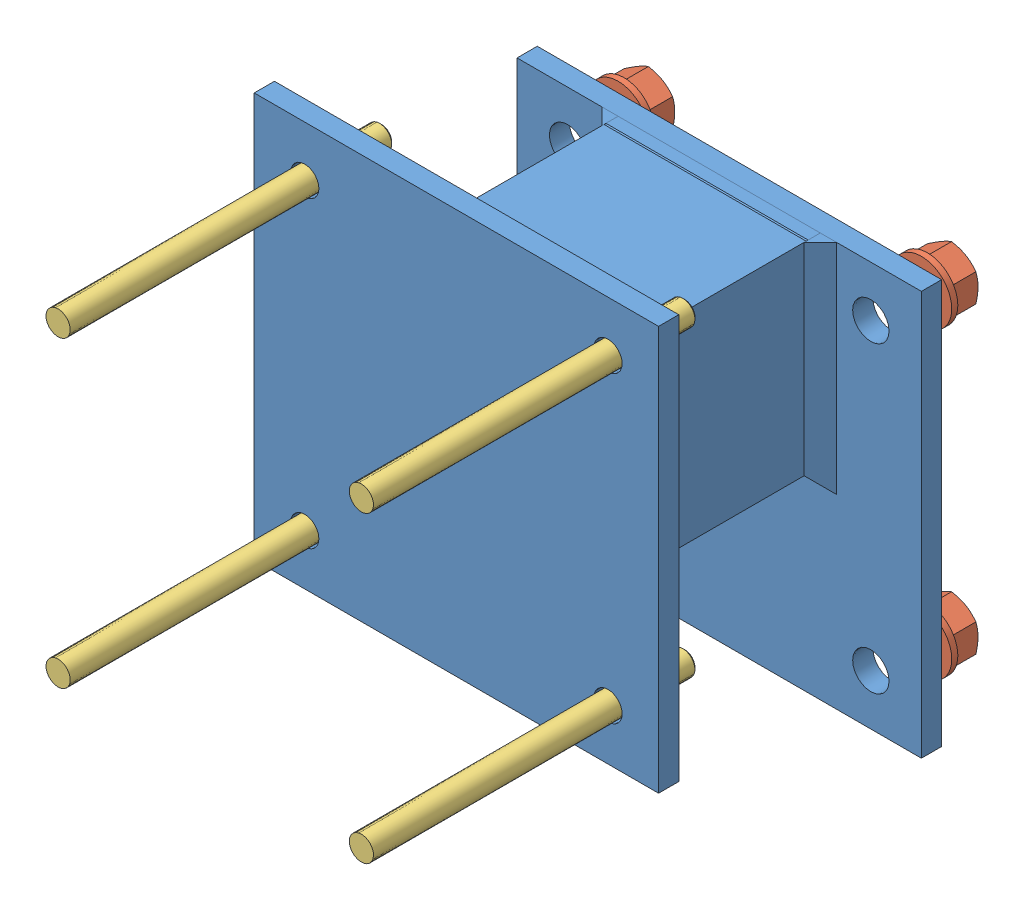
SolidWorks assembly 0408-JOINT ASSEMBLAGE, configuration Predeterminado. Lengths in mm.
Overall size (200 250 309).
13 component instances, 4 part files, 24 mates.
Components (placement in the parent):
- 0414-WALL JOINT-1: 0414-WALL JOINT [Predeterminado<Como mecanizada>] at (-5.3755 60.3266 0) size (200 250 140)
- M-16x60 DIN-6914-18 and DIN-6916-1: M-16x60 DIN-6914-18 and DIN-6916 [DIN 6914 - M20 x 65 x 31-N] at (-80.3755 85.3266 -44) x (0 0 -1) z (1 0 0) size (73 30 30)
- M-16x60 DIN-6914-18 and DIN-6916-2: M-16x60 DIN-6914-18 and DIN-6916 [DIN 6914 - M20 x 65 x 31-N] at (69.6245 85.3266 -44) x (0 0 -1) z (1 0 0) size (73 30 30)
- M-16x60 DIN-6914-18 and DIN-6916-3: M-16x60 DIN-6914-18 and DIN-6916 [DIN 6914 - M20 x 65 x 31-N] at (69.6245 -64.6734 -44) x (0 0 -1) z (1 0 0) size (73 30 30)
- M-16x60 DIN-6914-18 and DIN-6916-4: M-16x60 DIN-6914-18 and DIN-6916 [DIN 6914 - M20 x 65 x 31-N] at (-80.3755 -64.6734 -44) x (0 0 -1) z (1 0 0) size (73 30 30)
- M-16 DIN-6915 and DIN-6916-1: M-16 DIN-6915 and DIN-6916 [Hexagon Nut DIN 6915 - M20 - N] at (-80.3755 85.3266 -88) size (30 30 16)
- M-16 DIN-6915 and DIN-6916-2: M-16 DIN-6915 and DIN-6916 [Hexagon Nut DIN 6915 - M20 - N] at (69.6245 85.3266 -88) size (30 30 16)
- M-16 DIN-6915 and DIN-6916-3: M-16 DIN-6915 and DIN-6916 [Hexagon Nut DIN 6915 - M20 - N] at (-80.3755 -64.6734 -88) size (30 30 16)
- M-16 DIN-6915 and DIN-6916-4: M-16 DIN-6915 and DIN-6916 [Hexagon Nut DIN 6915 - M20 - N] at (69.6245 -64.6734 -88) size (30 30 16)
- M-12x160 CHEMICAL ANCHOR-1: M-12x160 CHEMICAL ANCHOR [DIN 525 - M20 x 210 --- 75N] at (-80.3755 135.3266 192) x (0 0 -1) z (-0.313124 -0.949712 0) size (160 24 24)
- M-12x160 CHEMICAL ANCHOR-2: M-12x160 CHEMICAL ANCHOR [DIN 525 - M20 x 210 --- 75N] at (-80.3755 -14.6734 192) x (0 0 -1) z (-0.313124 -0.949712 0) size (160 24 24)
- M-12x160 CHEMICAL ANCHOR-3: M-12x160 CHEMICAL ANCHOR [DIN 525 - M20 x 210 --- 75N] at (69.6245 135.3266 192) x (0 0 -1) z (-0.313124 -0.949712 0) size (160 24 24)
- M-12x160 CHEMICAL ANCHOR-4: M-12x160 CHEMICAL ANCHOR [DIN 525 - M20 x 210 --- 75N] at (69.6245 -14.6734 192) x (0 0 -1) z (-0.313124 -0.949712 0) size (160 24 24)
Mates (geometry in assembly coordinates):
- Coincidente1: coincident anti-aligned: plane of 0414-WALL JOINT-1 through (94.6245 -89.6734 -60) normal (0 0 1); plane of M-16x60 DIN-6914-18 and DIN-6916-1 through (-80.3755 85.3266 -60) normal (0 0 -1)
- Concéntrica1: concentric aligned: cylinder of 0414-WALL JOINT-1 through (-80.3755 85.3266 -70) axis (0 0 1) radius 9; cylinder of M-16x60 DIN-6914-18 and DIN-6916-1 through (-80.3755 85.3266 -44) axis (0 0 1) radius 8
- Coincidente2: coincident anti-aligned: plane of 0414-WALL JOINT-1 through (94.6245 -89.6734 -60) normal (0 0 1); plane of M-16x60 DIN-6914-18 and DIN-6916-2 through (69.6245 85.3266 -60) normal (0 0 -1)
- Concéntrica2: concentric aligned: cylinder of 0414-WALL JOINT-1 through (69.6245 85.3266 -70) axis (0 0 1) radius 9; cylinder of M-16x60 DIN-6914-18 and DIN-6916-2 through (69.6245 85.3266 -44) axis (0 0 1) radius 8
- Coincidente3: coincident anti-aligned: plane of 0414-WALL JOINT-1 through (94.6245 -89.6734 -60) normal (0 0 1); plane of M-16x60 DIN-6914-18 and DIN-6916-3 through (69.6245 -64.6734 -60) normal (0 0 -1)
- Concéntrica3: concentric aligned: cylinder of 0414-WALL JOINT-1 through (69.6245 -64.6734 -70) axis (0 0 1) radius 9; cylinder of M-16x60 DIN-6914-18 and DIN-6916-3 through (69.6245 -64.6734 -44) axis (0 0 1) radius 8
- Coincidente4: coincident anti-aligned: plane of 0414-WALL JOINT-1 through (94.6245 -89.6734 -60) normal (0 0 1); plane of M-16x60 DIN-6914-18 and DIN-6916-4 through (-80.3755 -64.6734 -60) normal (0 0 -1)
- Concéntrica4: concentric aligned: cylinder of 0414-WALL JOINT-1 through (-80.3755 -64.6734 -70) axis (0 0 1) radius 9; cylinder of M-16x60 DIN-6914-18 and DIN-6916-4 through (-80.3755 -64.6734 -44) axis (0 0 1) radius 8
- Distancia1: distance = 15 mm anti-aligned: plane of M-16 DIN-6915 and DIN-6916-1 through (-80.3755 85.3266 -85) normal (0 0 1); plane of 0414-WALL JOINT-1 through (94.6245 -89.6734 -70) normal (0 0 -1)
- Concéntrica5: concentric aligned: cylinder of M-16x60 DIN-6914-18 and DIN-6916-1 through (-80.3755 85.3266 -44) axis (0 0 1) radius 8; cylinder of M-16 DIN-6915 and DIN-6916-1 through (-80.3755 85.3266 -101) axis (0 0 1) radius 8
- Distancia2: distance = 15 mm anti-aligned: plane of M-16 DIN-6915 and DIN-6916-2 through (69.6245 85.3266 -85) normal (0 0 1); plane of 0414-WALL JOINT-1 through (94.6245 -89.6734 -70) normal (0 0 -1)
- Concéntrica6: concentric aligned: cylinder of M-16x60 DIN-6914-18 and DIN-6916-2 through (69.6245 85.3266 -44) axis (0 0 1) radius 8; cylinder of M-16 DIN-6915 and DIN-6916-2 through (69.6245 85.3266 -101) axis (0 0 1) radius 8
- Distancia3: distance = 15 mm anti-aligned: plane of M-16 DIN-6915 and DIN-6916-3 through (-80.3755 -64.6734 -85) normal (0 0 1); plane of 0414-WALL JOINT-1 through (94.6245 -89.6734 -70) normal (0 0 -1)
- Concéntrica7: concentric aligned: cylinder of M-16x60 DIN-6914-18 and DIN-6916-4 through (-80.3755 -64.6734 -44) axis (0 0 1) radius 8; cylinder of M-16 DIN-6915 and DIN-6916-3 through (-80.3755 -64.6734 -101) axis (0 0 1) radius 8
- Distancia4: distance = 15 mm anti-aligned: plane of M-16 DIN-6915 and DIN-6916-4 through (69.6245 -64.6734 -85) normal (0 0 1); plane of 0414-WALL JOINT-1 through (94.6245 -89.6734 -70) normal (0 0 -1)
- Concéntrica8: concentric aligned: cylinder of M-16x60 DIN-6914-18 and DIN-6916-3 through (69.6245 -64.6734 -44) axis (0 0 1) radius 8; cylinder of M-16 DIN-6915 and DIN-6916-4 through (69.6245 -64.6734 -101) axis (0 0 1) radius 8
- Concéntrica9: concentric anti-aligned: cylinder of M-12x160 CHEMICAL ANCHOR-1 through (-80.3755 135.3266 223.75) axis (0 0 1) radius 6; cylinder of 0414-WALL JOINT-1 through (-80.3755 135.3266 70) axis (0 0 -1) radius 7
- Coincidente5: coincident anti-aligned: plane of 0414-WALL JOINT-1 through (-105.3755 -39.6734 60) normal (0 0 -1); plane of M-12x160 CHEMICAL ANCHOR-1 through (-80.3755 135.3266 60) normal (0 0 1)
- Concéntrica10: concentric anti-aligned: cylinder of M-12x160 CHEMICAL ANCHOR-2 through (-80.3755 -14.6734 223.75) axis (0 0 1) radius 6; cylinder of 0414-WALL JOINT-1 through (-80.3755 -14.6734 70) axis (0 0 -1) radius 7
- Coincidente6: coincident anti-aligned: plane of 0414-WALL JOINT-1 through (-105.3755 -39.6734 60) normal (0 0 -1); plane of M-12x160 CHEMICAL ANCHOR-2 through (-80.3755 -14.6734 60) normal (0 0 1)
- Concéntrica11: concentric anti-aligned: cylinder of M-12x160 CHEMICAL ANCHOR-3 through (69.6245 135.3266 223.75) axis (0 0 1) radius 6; cylinder of 0414-WALL JOINT-1 through (69.6245 135.3266 70) axis (0 0 -1) radius 7
- Coincidente7: coincident anti-aligned: plane of 0414-WALL JOINT-1 through (-105.3755 -39.6734 60) normal (0 0 -1); plane of M-12x160 CHEMICAL ANCHOR-3 through (69.6245 135.3266 60) normal (0 0 1)
- Concéntrica12: concentric anti-aligned: cylinder of M-12x160 CHEMICAL ANCHOR-4 through (69.6245 -14.6734 223.75) axis (0 0 1) radius 6; cylinder of 0414-WALL JOINT-1 through (69.6245 -14.6734 70) axis (0 0 -1) radius 7
- Coincidente8: coincident anti-aligned: plane of 0414-WALL JOINT-1 through (-105.3755 -39.6734 60) normal (0 0 -1); plane of M-12x160 CHEMICAL ANCHOR-4 through (69.6245 -14.6734 60) normal (0 0 1)
